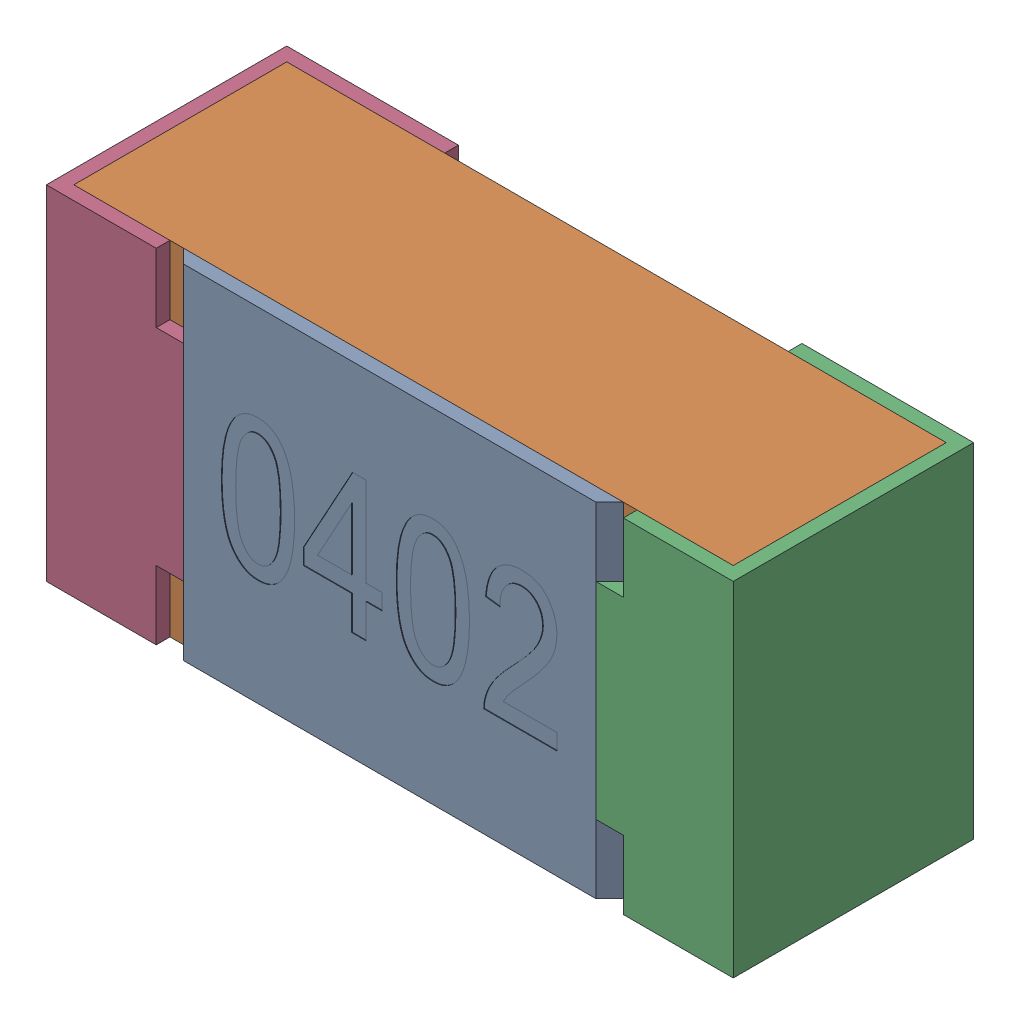
SolidWorks assembly R12, configuration Standard. Lengths in mm.
Overall size (1 0.5 0.35).
5 component instances, 4 part files, 0 mates.
Components (placement in the parent):
- R12-subassembly-1-1: R12-subassembly-1 [Standard] at (8.6001 -9.5 0) x (1 0 0) z (0 0 1) size (1 0.5 0.35)
  - User Library-R_0402-1: User Library-R_0402 [Standard] at origin size (0.64 0.5 0.02)
  - User Library-R_0402-1-1: User Library-R_0402-1 [Standard] at origin size (0.96 0.5 0.31)
  - User Library-R_0402-2-1: User Library-R_0402-2 [Standard] at origin size (0.25 0.5 0.35)
  - User Library-R_0402-3-1: User Library-R_0402-3 [Standard] at origin size (0.25 0.5 0.35)
